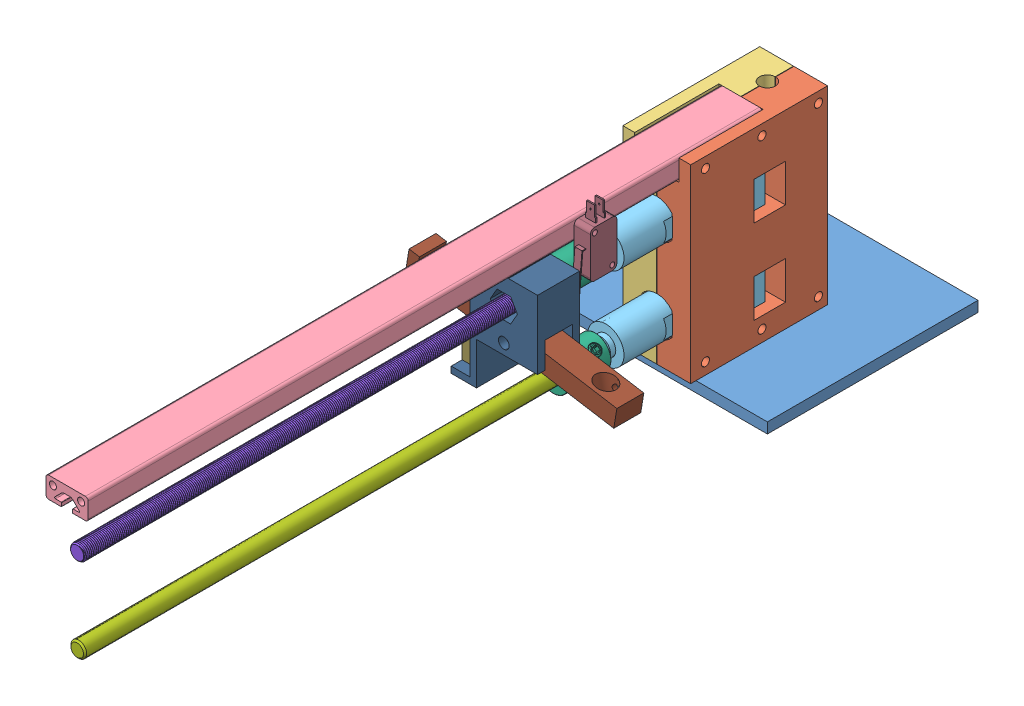
SolidWorks assembly Plotter_v3, configuration Default. Lengths in mm.
Overall size (127.17 128.1 485.78).
22 component instances, 17 part files, 58 mates.
Components (placement in the parent):
- Base-2: Base [Default] at origin size (127 107.95 127)
- Motor Mount Wire Side-2: Motor Mount Wire Side [Wire Side] at (20.447 57.15 66.675) x (0 -1 0) z (0 0 -1) size (114.3 20.32 82.55)
- Motor Mount-3: Motor Mount [Default] at (-20.447 57.15 66.675) x (0 1 0) z (0 0 -1) size (114.3 20.32 82.55)
- T-Slotted Framing Rail-1: T-Slotted Framing Rail [6575N215] at (0 120.65 219.075) x (-1 0 0) z (0 0 1) size (25.4 12.7 406.4)
- Motor-1: Motor [Default] at (0 82.55 15.875) x (0 -1 0) z (0 0 1) size (21.97 25.4 95.5)
- Motor-2: Motor [Default] at (0 31.75 15.875) x (0 -1 0) z (0 0 1) size (21.97 25.4 95.5)
- Set Screw Shaft Coupling-1: Set Screw Shaft Coupling [6412K13] at (0 82.55 116.459) x (0.31595 0.948776 0) z (0 0 1) size (19.05 20.32 25.4)
- Set Screw Shaft Coupling-2: Set Screw Shaft Coupling [6412K13] at (0 31.75 116.459) x (0.737163 -0.675715 0) z (0 0 1) size (19.05 20.32 25.4)
- Rotary Shaft-1: Rotary Shaft [1346K11] at (0 31.75 263.779) x (0.675715 0.737163 0) z (0 0 1) size (9.53 9.53 304.8)
- .375 Steel Threaded Rod-1: .375 Steel Threaded Rod [98791A051] at (0 82.55 416.179) x (-0.948776 0.31595 0) z (0 0 1) size (10 9.69 305.84)
- .375 Steel Hex Nut-1: .375 Steel Hex Nut [95505A613] at (0 82.55 146.2071) x (0 -1 0) z (0 0 -1) size (14.1 16.28 9.1)
- Lead Screw Mount-1: Lead Screw Mount [Default] at (0 82.55 376.2318) size (40.89 109.22 38.1) (hidden)
- Bearing-1: Bearing [Default] at (0 82.55 357.1818) x (0.998334 -0.057696 0) z (-0.057696 -0.998334 0) size (22.23 7.14 22.23) (hidden)
- Bearing-2: Bearing [Default] at (0 31.75 364.3255) x (0.986045 -0.16648 0) z (0.16648 0.986045 0) size (22.23 7.14 22.23) (hidden)
- Bearing-3: Bearing [Default] at (0 31.75 395.2818) x (-0.156795 -0.987631 0) z (0.987631 -0.156795 0) size (22.23 7.14 22.23) (hidden)
- Bearing-4: Bearing [Default] at (0 82.55 388.138) x (0.997979 0.063542 0) z (0.063542 -0.997979 0) size (22.23 7.14 22.23) (hidden)
- TrackSliderv3-1: TrackSliderv3 [Default] at (0 82.55 146.2071) size (52.07 83.67 25.4)
- Solenoid-1: Solenoid [Retracted] at (-26.0096 45.8851 146.2071) size (12.65 29.67 12.19) (hidden)
- Seesaw_v2-1: Seesaw_v2 [Default] at (0 63.5 146.2071) x (0.986656 -0.162817 0) z (0 0 1) size (127 11.43 16.26)
- Solenoid Extended-1: Solenoid Extended [Retracted] at (-26.0096 45.8851 146.2071) size (12.65 29.77 12.19)
- Limit Switch-1: Limit Switch [Default] at (17.5641 104.999 121.1976) x (0 0 -1) z (1 0 0) size (26.74 47.7 9.73)
- Wheel-1: Wheel [Default] at (0 31.75 415.2265) x (0.970916 -0.239419 0) z (0.239419 0.970916 0) size (50.8 6.35 50.8) (hidden)
Mates (geometry in assembly coordinates):
- Coincident1: coordinate: point of Base-2
- Concentric1: concentric aligned: cylinder of Base-2 through (0 107.95 0) axis (0 -1 0) radius 4.7625; cylinder of Motor Mount-3 through (0 134.3 0) axis (0 -1 0) radius 4.826
- Concentric2: concentric anti-aligned: cylinder of Base-2 through (0 107.95 0) axis (0 -1 0) radius 4.7625; cylinder of Motor Mount Wire Side-2 through (0 -7.3 0) axis (0 1 0) radius 4.826
- Coincident2: coincident anti-aligned: plane of Base-2 through (0 6.35 0) normal (0 1 0); plane of Motor Mount Wire Side-2 through (20.447 6.35 28.575) normal (0 -1 0)
- Coincident3: coincident anti-aligned: plane of Base-2 through (0 6.35 0) normal (0 1 0); plane of Motor Mount-3 through (-20.447 6.35 28.575) normal (0 -1 0)
- Parallel1: parallel anti-aligned: plane of Motor Mount Wire Side-2 through (20.447 57.15 66.675) normal (0 0 -1)
- Parallel2: parallel anti-aligned: plane of Motor Mount-3 through (-20.447 57.15 66.675) normal (0 0 -1)
- Coincident6: coincident anti-aligned: plane of Motor Mount-3 through (-20.447 107.95 28.575) normal (0 1 0); plane of T-Slotted Framing Rail-1 through (-3.302 107.95 422.275) normal (0 -1 0)
- Coincident7: coincident anti-aligned: plane of Motor Mount-3 through (-20.447 120.65 15.875) normal (0 0 1); plane of T-Slotted Framing Rail-1 through (11.049 109.601 15.875) normal (0 0 -1)
- Coincident8: coincident anti-aligned: plane of T-Slotted Framing Rail-1 through (0 120.65 219.075) normal (-1 0 0)
- Coincident9: coincident anti-aligned: plane of Motor Mount Wire Side-2 through (50.2041 20.32 28.575) normal (0 0 -1); plane of Motor-2 through (0 31.75 28.575) normal (0 0 1)
- Parallel3: parallel aligned: plane of Motor-2 through (0 31.75 15.875) normal (1 0 0)
- Width2: width anti-aligned: plane of Motor-2 through (-9.398 37.4385 72.009) normal (-1 0 0); plane of Motor-2 through (9.398 37.4385 72.009) normal (1 0 0); plane of Motor Mount-3 through (-9.017 24.5658 28.575) normal (1 0 0); plane of Motor Mount Wire Side-2 through (9.017 24.5658 28.575) normal (-1 0 0)
- Width3: width anti-aligned: plane of Motor-2 through (14.4145 20.7645 28.575) normal (0 -1 0); plane of Motor-2 through (0 42.7355 28.575) normal (0 1 0); plane of Motor Mount Wire Side-2 through (50.2041 20.32 28.575) normal (0 1 0); plane of Motor Mount Wire Side-2 through (50.2041 43.18 28.575) normal (0 -1 0)
- Parallel4: parallel aligned: plane of Motor-1 through (0 82.55 15.875) normal (1 0 0)
- Coincident13: coincident anti-aligned: plane of Motor Mount Wire Side-2 through (50.2041 93.98 28.575) normal (0 0 -1); plane of Motor-1 through (0 82.55 28.575) normal (0 0 1)
- Parallel5: parallel aligned: plane of Motor-1 through (0 82.55 15.875) normal (1 0 0)
- Width4: width anti-aligned: plane of Motor-1 through (14.4145 71.5645 28.575) normal (0 -1 0); plane of Motor-1 through (0 93.5355 28.575) normal (0 1 0); plane of Motor Mount Wire Side-2 through (50.2041 71.12 28.575) normal (0 1 0); plane of Motor Mount Wire Side-2 through (50.2041 93.98 28.575) normal (0 -1 0)
- Width5: width anti-aligned: plane of Motor-1 through (-9.398 88.2385 72.009) normal (-1 0 0); plane of Motor-1 through (9.398 88.2385 72.009) normal (1 0 0); plane of Motor Mount-3 through (-9.017 89.7342 28.575) normal (1 0 0); plane of Motor Mount Wire Side-2 through (9.017 89.7342 28.575) normal (-1 0 0)
- Concentric3: concentric aligned: cylinder of Motor-1 through (0 82.55 111.379) axis (0 0 -1) radius 4.7625; cylinder of Set Screw Shaft Coupling-1 through (0 82.55 129.159) axis (0 0 -1) radius 4.7625
- Concentric4: concentric aligned: cylinder of Motor-2 through (0 31.75 111.379) axis (0 0 -1) radius 4.7625; cylinder of Set Screw Shaft Coupling-2 through (0 31.75 129.159) axis (0 0 -1) radius 4.7625
- Coincident19: coincident aligned: plane of Motor-1 through (0 82.55 103.759) normal (0 0 -1); plane of Set Screw Shaft Coupling-1 through (0 82.55 103.759) normal (0 0 -1)
- Coincident20: coincident aligned: plane of Motor-2 through (0 31.75 103.759) normal (0 0 -1); plane of Set Screw Shaft Coupling-2 through (0 31.75 103.759) normal (0 0 -1)
- Coincident21: coincident anti-aligned: plane of Motor-1 through (0 82.55 111.379) normal (0 0 1); plane of .375 Steel Threaded Rod-1 through (0 82.55 111.379) normal (0 0 -1)
- Coincident22: coincident anti-aligned: plane of Motor-2 through (0 31.75 111.379) normal (0 0 1); plane of Rotary Shaft-1 through (0 31.75 111.379) normal (0 0 -1)
- Concentric5: concentric aligned: cylinder of Set Screw Shaft Coupling-2 through (0 31.75 129.159) axis (0 0 -1) radius 4.7625; cylinder of Rotary Shaft-1 through (0 31.75 416.179) axis (0 0 -1) radius 4.7625
- Concentric6: concentric anti-aligned: cylinder of Set Screw Shaft Coupling-1 through (0 82.55 129.159) axis (0 0 -1) radius 4.7625; circle of .375 Steel Threaded Rod-1
- Coincident23: coincident aligned: plane of Set Screw Shaft Coupling-2 through (0 31.75 116.459) normal (0.675715 0.737163 0); plane of Rotary Shaft-1 through (0 31.75 263.779) normal (0.675715 0.737163 0)
- Coincident24: coincident aligned: plane of Set Screw Shaft Coupling-1 through (0 82.55 116.459) normal (-0.948776 0.31595 0); plane of .375 Steel Threaded Rod-1 through (0 82.55 416.179) normal (-0.948776 0.31595 0)
- Concentric8: concentric aligned: circle of Set Screw Shaft Coupling-1; circle of .375 Steel Hex Nut-1
- Screw1: screw = 1 aligned: cylinder of .375 Steel Threaded Rod-1 through (0 82.55 416.179) axis (0 0 1) radius 4.7625; cylinder of .375 Steel Hex Nut-1 through (0 82.55 142.0796) axis (0 0 1) radius 4.7625
- Parallel8: parallel anti-aligned: plane of T-Slotted Framing Rail-1 through (-1.6565 115.824 422.275) normal (0 -1 0); plane of .375 Steel Hex Nut-1 through (-4.0695 89.5985 142.0796) normal (0 1 0)
- Concentric9: concentric anti-aligned: cylinder of Rotary Shaft-1 through (0 31.75 416.179) axis (0 0 -1) radius 4.7625; cylinder of Bearing-2 through (0 31.75 357.1818) axis (0 0 1) radius 4.7625
- Concentric10: concentric aligned: cylinder of Lead Screw Mount-1 through (0 31.75 388.0428) axis (0 0 1) radius 11.176; cylinder of Bearing-2 through (0 31.75 357.1818) axis (0 0 1) radius 11.1125
- Concentric11: concentric anti-aligned: circle of .375 Steel Threaded Rod-1; cylinder of Bearing-1 through (0 82.55 364.3255) axis (0 0 -1) radius 4.7625
- Concentric12: concentric anti-aligned: cylinder of Lead Screw Mount-1 through (0 82.55 388.0428) axis (0 0 1) radius 11.176; cylinder of Bearing-1 through (0 82.55 364.3255) axis (0 0 -1) radius 11.1125
- Concentric13: concentric anti-aligned: cylinder of Rotary Shaft-1 through (0 31.75 416.179) axis (0 0 -1) radius 4.7625; cylinder of Bearing-3 through (0 31.75 388.138) axis (0 0 1) radius 4.7625
- Concentric14: concentric anti-aligned: circle of .375 Steel Threaded Rod-1; cylinder of Bearing-4 through (0 82.55 395.2818) axis (0 0 -1) radius 4.7625
- Coincident25: coincident aligned: plane of Lead Screw Mount-1 through (0 82.55 395.2818) normal (0 0 1); plane of Bearing-3 through (0 31.75 395.2818) normal (0 0 1)
- Coincident27: coincident aligned: plane of Lead Screw Mount-1 through (0 82.55 395.2818) normal (0 0 1); plane of Bearing-4 through (0 82.55 395.2818) normal (0 0 1)
- Coincident28: coincident aligned: plane of Lead Screw Mount-1 through (0 82.55 357.1818) normal (0 0 -1); plane of Bearing-1 through (0 82.55 357.1818) normal (0 0 -1)
- Coincident29: coincident aligned: plane of Lead Screw Mount-1 through (0 82.55 357.1818) normal (0 0 -1); plane of Bearing-2 through (0 31.75 357.1818) normal (0 0 -1)
- Width7: width anti-aligned: plane of TrackSliderv3-1 through (4.1061 75.438 158.9071) normal (-0.866025 0.5 0); plane of .375 Steel Hex Nut-1 through (-4.1061 89.662 158.9071) normal (0.866025 -0.5 0); plane of TrackSliderv3-1 through (8.1389 82.55 142.0796) normal (0.866025 -0.5 0); plane of .375 Steel Hex Nut-1 through (-8.1389 82.55 142.0796) normal (-0.866025 0.5 0)
- Width8: width anti-aligned: plane of .375 Steel Hex Nut-1 through (4.0695 89.5985 142.0796) normal (0.866025 0.5 0); plane of TrackSliderv3-1 through (-4.0695 75.5015 142.0796) normal (-0.866025 -0.5 0); plane of .375 Steel Hex Nut-1 through (8.2122 82.55 158.9071) normal (-0.866025 -0.5 0); plane of TrackSliderv3-1 through (-8.2122 82.55 158.9071) normal (0.866025 0.5 0)
- Width9: width anti-aligned: plane of TrackSliderv3-1 through (4.1061 89.662 158.9071) normal (0 -1 0); plane of .375 Steel Hex Nut-1 through (-4.1061 75.438 158.9071) normal (0 1 0); plane of TrackSliderv3-1 through (-4.0695 89.5985 142.0796) normal (0 1 0); plane of .375 Steel Hex Nut-1 through (4.0695 75.5015 142.0796) normal (0 -1 0)
- Coincident32: coincident anti-aligned: plane of .375 Steel Hex Nut-1 through (0 82.55 146.2071) normal (0 0 -1); plane of TrackSliderv3-1 through (0 82.55 146.2071) normal (0 0 1)
- Coincident33: coincident anti-aligned: plane of TrackSliderv3-1 through (-20.32 98.552 158.9071) normal (-1 0 0); plane of Solenoid-1 through (-20.32 45.8851 146.2071) normal (1 0 0)
- Coincident34: coincident aligned: plane of TrackSliderv3-1 through (0 82.55 146.2071) normal (0 0 1); plane of Solenoid-1 through (-26.0096 45.8851 146.2071) normal (0 0 1)
- Coincident35: coincident anti-aligned: plane of TrackSliderv3-1 through (-20.32 35.56 188.5284) normal (0 1 0); plane of Solenoid-1 through (-20.32 35.56 140.1111) normal (0 -1 0)
- Concentric15: concentric aligned: cylinder of TrackSliderv3-1 through (0 63.5 124.3473) axis (0 0 1) radius 3.2385; cylinder of Seesaw_v2-1 through (0 63.5 127.3028) axis (0 0 1) radius 3.81
- Width11: width anti-aligned: plane of TrackSliderv3-1 through (-31.75 57.15 154.4621) normal (0 0 -1); plane of TrackSliderv3-1 through (-31.75 72.898 137.9521) normal (0 0 1); plane of Seesaw_v2-1 through (0 63.5 154.3351) normal (0 0 1); plane of Seesaw_v2-1 through (0 63.5 138.0791) normal (0 0 -1)
- Coincident37: coincident anti-aligned: plane of TrackSliderv3-1 through (-20.32 98.552 158.9071) normal (-1 0 0); plane of Solenoid Extended-1 through (-20.32 45.8851 146.2071) normal (1 0 0)
- Coincident38: coincident anti-aligned: plane of TrackSliderv3-1 through (-20.32 35.56 188.5284) normal (0 1 0); plane of Solenoid Extended-1 through (-20.32 35.56 140.1111) normal (0 -1 0)
- Coincident39: coincident aligned: plane of TrackSliderv3-1 through (0 82.55 146.2071) normal (0 0 1); plane of Solenoid Extended-1 through (-26.0096 45.8851 146.2071) normal (0 0 1)
- Coincident40: coincident anti-aligned: plane of T-Slotted Framing Rail-1 through (12.7 109.601 422.275) normal (1 0 0); plane of Limit Switch-1 through (12.7 93.539 115.7376) normal (-1 0 0)
- Coincident41: coincident: line of T-Slotted Framing Rail-1 through (12.7 118.999 422.275) axis (0 0 -1); plane of Limit Switch-1 through (22.4282 118.999 115.7376) normal (0 1 0)
- Concentric16: concentric anti-aligned: cylinder of Rotary Shaft-1 through (0 31.75 416.179) axis (0 0 -1) radius 4.7625; cylinder of Wheel-1 through (0 31.75 408.8765) axis (0 0 1) radius 4.7625
- Coincident42: coincident anti-aligned: circle of Rotary Shaft-1; plane of Wheel-1 through (0 31.75 415.2265) normal (0 0 1)
